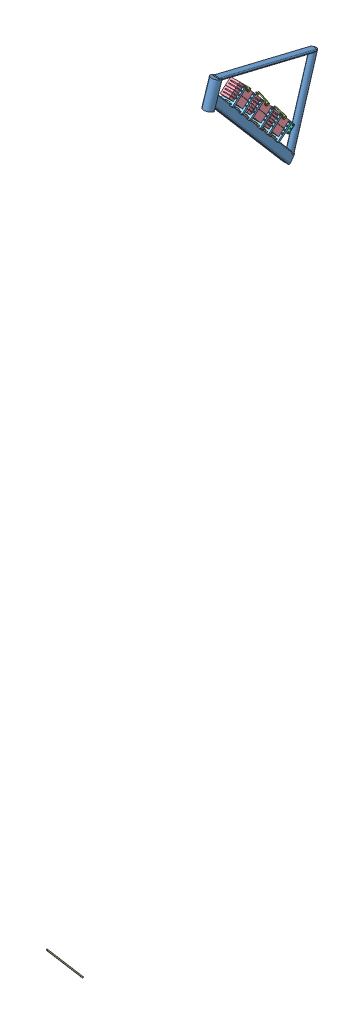
SolidWorks assembly Battery_holder_v2, configuration Défaut. Lengths in mm.
Overall size (1403.22 2518.36 2875.14).
21 component instances, 7 part files, 55 mates.
Components (placement in the parent):
- Cadre_Velo-1: Cadre_Velo [Défaut] at origin size (50 640.17 698.01)
- Bottle holder adaptater-1: Bottle holder adaptater [Défaut] at (0 182.5535 124.6605) x (1 0 0) z (0 0.759271 0.650774) size (57.1 12 20)
- Bottle holder adaptater-2: Bottle holder adaptater [Défaut] at (0 231.9062 166.9608) x (1 0 0) z (0 0.759271 0.650774) size (57.1 12 20)
- Tige carbone-1: Tige carbone [Défaut] at (2187.7009 1636.9396 -1664.3987) x (-0.537917 -0.548601 0.640064) z (-0.842998 0.350062 -0.408425) size (6 295 6)
- Tige carbone-2: Tige carbone [Défaut] at (74.0331 -15.5477 263.5913) x (0.567345 -0.5359 0.625245) z (-0.82348 -0.369213 0.430769) size (6 295 6)
- Battery-1: Battery [Défaut] at (-24 378.7609 226.9779) x (1 0 0) z (0 0.759271 0.650774) size (56.53 37 140.81)
- Battery-7: Battery [Défaut] at (-24 354.0315 255.8302) x (1 0 0) z (0 0.759271 0.650774) size (56.53 37 140.81)
- Battery-8: Battery [Défaut] at (-24 242.4186 160.1664) x (1 0 0) z (0 0.759271 0.650774) size (56.53 37 140.81)
- Battery-9: Battery [Défaut] at (-24 155.5351 35.6503) x (1 0 0) z (0 0.759271 0.650774) size (56.53 37 140.81)
- Battery-10: Battery [Défaut] at (-24 267.148 131.3141) x (1 0 0) z (0 0.759271 0.650774) size (56.53 37 140.81)
- Battery-11: Battery [Défaut] at (-24 130.8057 64.5026) x (1 0 0) z (0 0.759271 0.650774) size (56.53 37 140.81)
- Battery_support-1: Battery_support [Défaut] at (0 225.7245 193.2717) x (1 0 0) z (0 0.759271 0.650774) size (68 94 10)
- Battery_support-2: Battery_support [Défaut] at (0 175.4866 150.2126) x (1 0 0) z (0 0.759271 0.650774) size (68 94 10)
- Battery_support-3: Battery_support [Défaut] at (0 291.2749 249.4552) x (1 0 0) z (0 0.759271 0.650774) size (68 94 10)
- Battery_support-4: Battery_support [Défaut] at (0 340.3969 291.5578) x (1 0 0) z (0 0.759271 0.650774) size (68 94 10)
- Battery_support-5: Battery_support [Défaut] at (0 400.1277 342.7533) x (1 0 0) z (0 0.759271 0.650774) size (68 94 10)
- Battery_support-6: Battery_support [Défaut] at (0 115.5635 98.8524) x (1 0 0) z (0 0.759271 0.650774) size (68 94 10)
- Separator-1: Separator [Défaut] at (-73.2085 168.4139 1.7792) x (1 0 0) z (0 0.759271 0.650774) size (68 60 3)
- Safety_clip^Battery_holder_v2-1: Safety_clip^Battery_holder_v2 [Défaut] at (12.4116 433.2176 259.0471) x (1 0 0) z (0 0.759271 0.650774) size (77.25 17.74 10) (virtual)
- Safety_clip^Battery_holder_v2-2: Safety_clip^Battery_holder_v2 [Défaut] at (9.3278 212.6829 65.7681) x (0.984227 -0.115128 0.134322) z (0 0.759271 0.650774) size (77.25 17.74 10) (virtual)
- Safety_clip^Battery_holder_v2-3: Safety_clip^Battery_holder_v2 [Défaut] at (8.1169 322.0366 157.3178) x (0.966558 -0.166889 0.194712) z (0 0.759271 0.650774) size (77.25 17.74 10) (virtual)
Mates (geometry in assembly coordinates):
- Coïncidente1: coincident: point of assembly; point of Cadre_Velo-1; point of Bottle holder adaptater-1
- Parallèle1: parallel anti-aligned: plane of Cadre_Velo-1 through (-10.0818 501.6498 398.1591) normal (0 0.650774 -0.759271); plane of Bottle holder adaptater-1 through (0 190.1462 131.1682) normal (0 -0.650774 0.759271)
- Parallèle2: parallel aligned: plane of Cadre_Velo-1 through (15.8982 -11.8116 13.7808) normal (0 -0.759271 -0.650774); plane of Bottle holder adaptater-1 through (0 174.9608 118.1527) normal (0 -0.759271 -0.650774)
- Coïncidente3: coincident anti-aligned: plane of Cadre_Velo-1 through (-10.0818 501.6498 398.1591) normal (0 0.650774 -0.759271); plane of Bottle holder adaptater-2 through (0 239.4989 173.4686) normal (0 -0.650774 0.759271)
- Parallèle3: parallel anti-aligned: plane of Bottle holder adaptater-1 through (0 190.1462 131.1682) normal (0 0.759271 0.650774); plane of Bottle holder adaptater-2 through (0 224.3135 160.4531) normal (0 -0.759271 -0.650774)
- Coaxiale5: concentric aligned: cylinder of Bottle holder adaptater-1 through (-22 189.4955 131.9275) axis (0 -0.759271 -0.650774) radius 3.25; cylinder of Bottle holder adaptater-2 through (-22 238.8481 174.2278) axis (0 -0.759271 -0.650774) radius 3.25
- Coïncidente4: coincident aligned: plane of Tige carbone-1 through (22 360.3315 278.3517) normal (0 0.759271 0.650774); plane of Tige carbone-2 through (1355.794 -1673.6768 2651.47) normal (0 0.759271 0.650774)
- Distance1: distance = 50 mm aligned: plane of Tige carbone-2 through (1355.794 -1897.6619 2459.4916) normal (0 -0.759271 -0.650774); plane of Bottle holder adaptater-1 through (0 174.9608 118.1527) normal (0 -0.759271 -0.650774)
- Parallèle4: parallel anti-aligned: plane of Cadre_Velo-1 through (-10.0818 501.6498 398.1591) normal (0 0.650774 -0.759271); plane of Battery-1 through (24 378.7609 226.9779) normal (0 -0.650774 0.759271)
- Coïncidente9: coincident aligned: plane of Cadre_Velo-1 through (0 0 0) normal (1 0 0); plane of Battery-1 through (0 378.7609 226.9779) normal (1 0 0)
- Coaxiale22: concentric aligned: circle of Cadre_Velo-1; cylinder of Bottle holder adaptater-2 through (0 227.3507 172.2757) axis (0 0.650774 -0.759271) radius 2.65
- Parallèle5: parallel anti-aligned: plane of Cadre_Velo-1 through (-10.0818 501.6498 398.1591) normal (0 0.650774 -0.759271); plane of Battery-5 through (22.8345 229.1238 52.8985) normal (0 -0.650774 0.759271)
- Parallèle6: parallel anti-aligned: plane of Cadre_Velo-1 through (-10.0818 501.6498 398.1591) normal (0 0.650774 -0.759271); plane of Battery-7 through (24 354.0315 255.8302) normal (0 -0.650774 0.759271)
- Coïncidente10: coincident aligned: plane of Cadre_Velo-1 through (0 0 0) normal (1 0 0); plane of Battery-7 through (0 354.0315 255.8302) normal (1 0 0)
- Parallèle7: parallel anti-aligned: plane of Cadre_Velo-1 through (-10.0818 501.6498 398.1591) normal (0 0.650774 -0.759271); plane of Battery-8 through (24 242.4186 160.1664) normal (0 -0.650774 0.759271)
- Coïncidente11: coincident aligned: plane of Cadre_Velo-1 through (0 0 0) normal (1 0 0); plane of Battery-8 through (0 242.4186 160.1664) normal (1 0 0)
- Coïncidente12: coincident aligned: plane of Cadre_Velo-1 through (0 0 0) normal (1 0 0); plane of Battery-9 through (0 155.5351 35.6503) normal (1 0 0)
- Parallèle8: parallel anti-aligned: plane of Cadre_Velo-1 through (-10.0818 501.6498 398.1591) normal (0 0.650774 -0.759271); plane of Battery-8 through (24 242.4186 160.1664) normal (0 -0.650774 0.759271)
- Parallèle9: parallel anti-aligned: plane of Cadre_Velo-1 through (-10.0818 501.6498 398.1591) normal (0 0.650774 -0.759271); plane of Battery-9 through (24 155.5351 35.6503) normal (0 -0.650774 0.759271)
- Coïncidente13: coincident aligned: plane of Cadre_Velo-1 through (0 0 0) normal (1 0 0); plane of Battery-10 through (0 267.148 131.3141) normal (1 0 0)
- Coïncidente14: coincident aligned: plane of Cadre_Velo-1 through (0 0 0) normal (1 0 0); plane of Battery-11 through (0 130.8057 64.5026) normal (1 0 0)
- Parallèle10: parallel anti-aligned: plane of Cadre_Velo-1 through (-10.0818 501.6498 398.1591) normal (0 0.650774 -0.759271); plane of Battery-9 through (24 155.5351 35.6503) normal (0 -0.650774 0.759271)
- Parallèle11: parallel anti-aligned: plane of Cadre_Velo-1 through (-10.0818 501.6498 398.1591) normal (0 0.650774 -0.759271); plane of Battery-11 through (24 130.8057 64.5026) normal (0 -0.650774 0.759271)
- Coïncidente15: coincident aligned: plane of Cadre_Velo-1 through (0 0 0) normal (1 0 0); plane of Battery-11 through (0 130.8057 64.5026) normal (1 0 0)
- Parallèle12: parallel aligned: plane of Battery-1 through (24 402.8395 198.8849) normal (0 0.650774 -0.759271); plane of Battery-10 through (24 291.2267 103.2211) normal (0 0.650774 -0.759271)
- Coïncidente16: coincident aligned: plane of Battery-1 through (24 402.8395 198.8849) normal (0 0.650774 -0.759271); plane of Battery-10 through (24 291.2267 103.2211) normal (0 0.650774 -0.759271)
- Coïncidente17: coincident aligned: plane of Battery-9 through (24 179.6138 7.5573) normal (0 0.650774 -0.759271); plane of Battery-10 through (24 291.2267 103.2211) normal (0 0.650774 -0.759271)
- Coïncidente18: coincident aligned: plane of Battery-7 through (24 378.1101 227.7372) normal (0 0.650774 -0.759271); plane of Battery-8 through (24 266.4972 132.0734) normal (0 0.650774 -0.759271)
- Coïncidente19: coincident aligned: plane of Battery-8 through (24 266.4972 132.0734) normal (0 0.650774 -0.759271); plane of Battery-11 through (24 154.8844 36.4096) normal (0 0.650774 -0.759271)
- Coïncidente20: coincident aligned: plane of Battery-1 through (24 378.7609 226.9779) normal (0 -0.759271 -0.650774); plane of Battery-7 through (24 354.0315 255.8302) normal (0 -0.759271 -0.650774)
- Coïncidente21: coincident aligned: plane of Battery-8 through (24 242.4186 160.1664) normal (0 -0.759271 -0.650774); plane of Battery-10 through (24 267.148 131.3141) normal (0 -0.759271 -0.650774)
- Coïncidente22: coincident aligned: plane of Battery-9 through (24 155.5351 35.6503) normal (0 -0.759271 -0.650774); plane of Battery-11 through (24 130.8057 64.5026) normal (0 -0.759271 -0.650774)
- Distance3: distance = 12 mm anti-aligned: plane of Battery-10 through (24 369.6496 219.1686) normal (0 0.759271 0.650774); plane of Battery-1 through (24 378.7609 226.9779) normal (0 -0.759271 -0.650774)
- Distance4: distance = 1 mm anti-aligned: plane of Battery-7 through (24 378.1101 227.7372) normal (0 0.650774 -0.759271); plane of Battery-1 through (24 378.7609 226.9779) normal (0 -0.650774 0.759271)
- Distance5: distance = 12 mm anti-aligned: plane of Battery-10 through (24 267.148 131.3141) normal (0 -0.759271 -0.650774); plane of Battery-9 through (24 258.0368 123.5048) normal (0 0.759271 0.650774)
- Distance6: distance = 7 mm anti-aligned: plane of Bottle holder adaptater-2 through (-28.5481 242.7528 169.6722) normal (0 0.650774 -0.759271); plane of Battery-8 through (24 242.4186 160.1664) normal (0 -0.650774 0.759271)
- Parallèle13: parallel aligned: plane of Battery_support-1 through (0 225.7245 193.2717) normal (0 0.759271 0.650774)
- Coïncidente23: coincident aligned: plane of Cadre_Velo-1 through (0 0 0) normal (1 0 0); plane of Battery_support-1 through (0 225.7245 193.2717) normal (1 0 0)
- Coaxiale23: concentric aligned: cylinder of Bottle holder adaptater-2 through (22 238.8481 174.2278) axis (0 -0.759271 -0.650774) radius 3.25; cylinder of Battery_support-1 through (22 248.285 182.3162) axis (0 -0.759271 -0.650774) radius 3.5
- Coaxiale24: concentric aligned: cylinder of Bottle holder adaptater-2 through (22 238.8481 174.2278) axis (0 -0.759271 -0.650774) radius 3.25; cylinder of Battery_support-2 through (22 198.0471 139.2571) axis (0 -0.759271 -0.650774) radius 3.5
- Parallèle14: parallel anti-aligned: plane of Cadre_Velo-1 through (-10.0818 501.6498 398.1591) normal (0 0.650774 -0.759271); plane of Battery_support-2 through (0 202.6025 133.9422) normal (0 -0.650774 0.759271)
- Coaxiale25: concentric aligned: cylinder of Bottle holder adaptater-1 through (22 189.4955 131.9275) axis (0 -0.759271 -0.650774) radius 3.25; cylinder of Tige carbone-1 through (22 360.3315 278.3517) axis (0 -0.759271 -0.650774) radius 3
- Coaxiale26: concentric aligned: cylinder of Tige carbone-1 through (22 360.3315 278.3517) axis (0 -0.759271 -0.650774) radius 3; cylinder of Battery_support-3 through (22 313.8354 238.4997) axis (0 -0.759271 -0.650774) radius 3.5
- Parallèle15: parallel aligned: plane of Battery_support-1 through (34 243.7296 187.6311) normal (1 0 0); plane of Battery_support-3 through (34 309.28 243.8146) normal (1 0 0)
- Parallèle16: parallel anti-aligned: plane of Battery-9 through (24 155.5351 35.6503) normal (0 -0.759271 -0.650774); plane of Separator-1 through (-73.2085 168.4139 1.7792) normal (0 0.759271 0.650774)
- Coaxiale27: concentric aligned: cylinder of Tige carbone-1 through (22 360.3315 278.3517) axis (0 -0.759271 -0.650774) radius 3; cylinder of Battery_support-4 through (22 362.9574 280.6024) axis (0 -0.759271 -0.650774) radius 3.5
- Coïncidente24: coincident aligned: plane of Battery_support-3 through (34 309.28 243.8146) normal (1 0 0); plane of Battery_support-4 through (34 358.402 285.9173) normal (1 0 0)
- Coaxiale28: concentric aligned: cylinder of Battery_support-6 through (29 190.8368 26.3959) axis (0 -0.759271 -0.650774) radius 3.25; cylinder of Separator-1 through (29 168.0245 6.8434) axis (0 -0.759271 -0.650774) radius 3.25
- Coaxiale29: concentric aligned: cylinder of Tige carbone-1 through (22 360.3315 278.3517) axis (0 -0.759271 -0.650774) radius 3; cylinder of Battery_support-6 through (22 138.124 87.8969) axis (0 -0.759271 -0.650774) radius 3.5
- Coïncidente25: coincident aligned: plane of Battery_support-2 through (34 193.4917 144.572) normal (1 0 0); plane of Separator-1 through (34 171.9292 2.2878) normal (1 0 0)
- Parallèle17: parallel anti-aligned: plane of Separator-1 through (-73.2085 168.4139 1.7792) normal (0 -0.759271 -0.650774); plane of Safety_clip^Battery_holder_v2-1 through (12.4116 433.2176 259.0471) normal (0 0.759271 0.650774)
- Coaxiale30: concentric aligned: cylinder of Battery_support-6 through (29 190.8368 26.3959) axis (0 -0.759271 -0.650774) radius 3.25; cylinder of Safety_clip^Battery_holder_v2-1 through (29 453.1166 251.1969) axis (0 -0.759271 -0.650774) radius 3.25
- Coaxiale31: concentric anti-aligned: circle of Battery_support-6; cylinder of Safety_clip^Battery_holder_v2-2 through (29 230.478 60.3725) axis (0 -0.759271 -0.650774) radius 3.25
- Coaxiale32: concentric anti-aligned: circle of Battery_support-1; cylinder of Safety_clip^Battery_holder_v2-3 through (29 338.7557 153.1777) axis (0 -0.759271 -0.650774) radius 3.25
- Parallèle18: parallel anti-aligned: plane of Battery-1 through (24 402.8395 198.8849) normal (0 0.650774 -0.759271); plane of Safety_clip^Battery_holder_v2-1 through (24 458.3228 245.1227) normal (0 -0.650774 0.759271)
